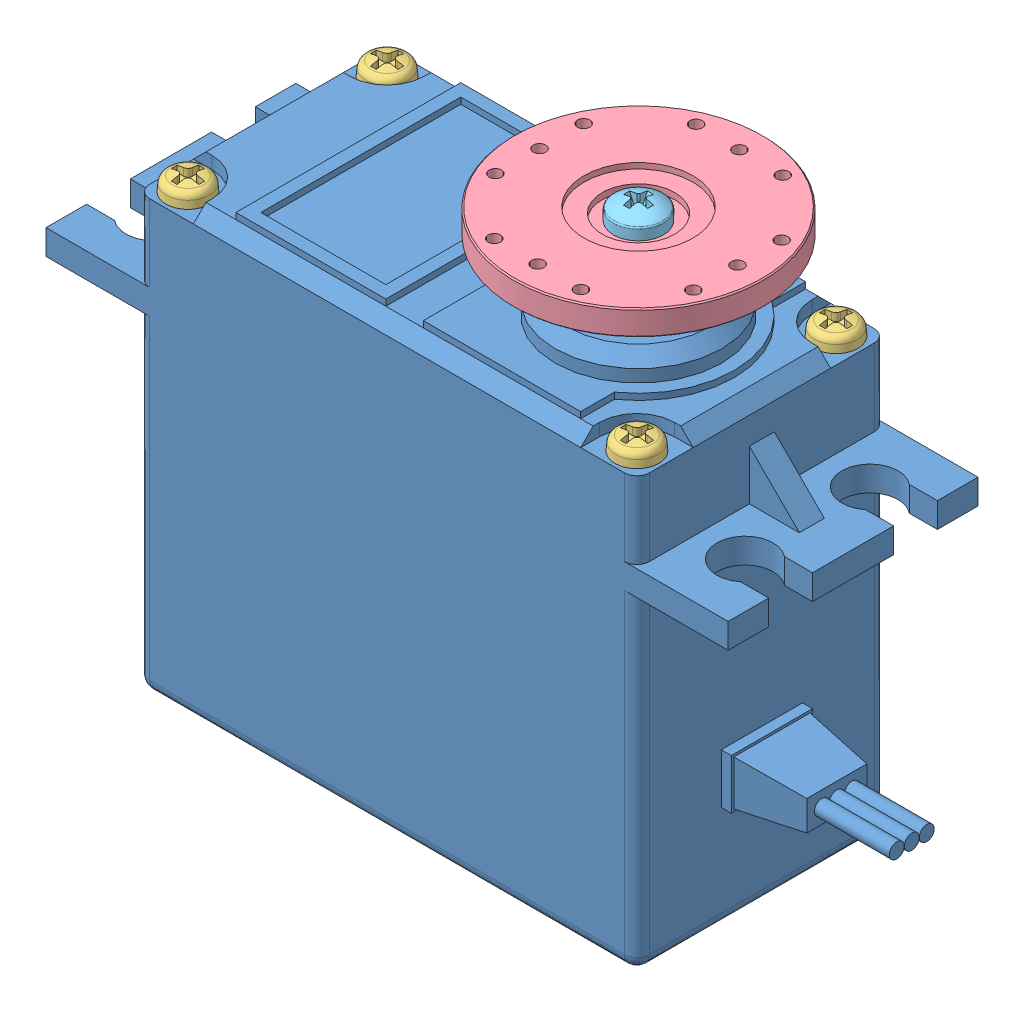
SolidWorks assembly servo_motor, configuration ﾃﾞﾌｫﾙﾄ. Lengths in mm.
Overall size (59.3 44.02 20.19).
8 component instances, 5 part files, 16 mates.
Components (placement in the parent):
- body-4: body [ﾃﾞﾌｫﾙﾄ] at (7.5879 13.1306 49.0124) size (59.3 37.9 20)
- spur gear_jis-4: spur gear_jis [JIS - Spur gear 0.25M 25T 20PA 6FW ---S25A75H50L2.0N] at (17.7129 55.0306 49.0124) x (0 -1 0) z (0 0 1) size (6 6.73 6.74)
- screw-6: screw [ﾃﾞﾌｫﾙﾄ] at (25.5576 47.5306 41.0427) x (0 -1 0) z (0 0 1) size (3.29 3.5 3.5)
- screw-7: screw [ﾃﾞﾌｫﾙﾄ] at (-10.3818 47.5306 41.0427) x (0 -1 0) z (0 0 1) size (3.29 3.5 3.5)
- screw-8: screw [ﾃﾞﾌｫﾙﾄ] at (25.5576 47.5306 56.9821) x (0 -1 0) z (0 0 1) size (3.29 3.5 3.5)
- screw-9: screw [ﾃﾞﾌｫﾙﾄ] at (-10.3818 47.5306 56.9821) x (0 -1 0) z (0 0 1) size (3.29 3.5 3.5)
- attachment-1: attachment [ﾃﾞﾌｫﾙﾄ] at (17.7129 56.5306 49.0124) x (-0.999954 0 -0.009565) z (-0.009565 0 0.999954) size (20 5 20)
- attachment_screw-1: attachment_screw [JIS B 1111 Cross recessed pan head screw - M2 x 5 - Z --5N] at (17.7129 57.1806 49.0124) x (0 -1 0) z (0 0 1) size (6.57 4 4)
Mates (geometry in assembly coordinates):
- 一致4: coincident anti-aligned: plane of ? through (-13.6217 41.271 50.2347) normal (0 1 0); plane of ? through (-13.6217 41.271 50.2347) normal (0 -1 0)
- 同心円4: concentric anti-aligned: circle of ?; circle of ?
- 一致6: coincident anti-aligned: plane of body-4 through (7.5879 47.5306 49.0124) normal (0 1 0); plane of screw-7 through (-8.6318 47.5306 41.0427) normal (0 -1 0)
- 同心円6: concentric aligned: cylinder of body-4 through (-10.3818 45.5306 41.0427) axis (0 1 0) radius 1; cylinder of screw-7 through (-10.3818 45.5306 41.0427) axis (0 1 0) radius 1
- 一致7: coincident anti-aligned: plane of body-4 through (7.5879 47.5306 49.0124) normal (0 1 0); plane of screw-6 through (27.3076 47.5306 41.0427) normal (0 -1 0)
- 同心円7: concentric aligned: cylinder of body-4 through (25.5576 45.5306 41.0427) axis (0 1 0) radius 1; cylinder of screw-6 through (25.5576 45.5306 41.0427) axis (0 1 0) radius 1
- 一致8: coincident anti-aligned: plane of body-4 through (7.5879 47.5306 49.0124) normal (0 1 0); plane of screw-8 through (27.3076 47.5306 56.9821) normal (0 -1 0)
- 同心円8: concentric aligned: cylinder of body-4 through (25.5576 45.5306 56.9821) axis (0 1 0) radius 1; cylinder of screw-8 through (25.5576 45.5306 56.9821) axis (0 1 0) radius 1
- 一致9: coincident anti-aligned: plane of body-4 through (7.5879 47.5306 49.0124) normal (0 1 0); plane of screw-9 through (-8.6318 47.5306 56.9821) normal (0 -1 0)
- 同心円9: concentric aligned: cylinder of body-4 through (-10.3818 45.5306 56.9821) axis (0 1 0) radius 1; cylinder of screw-9 through (-10.3818 45.5306 56.9821) axis (0 1 0) radius 1
- 一致10: coincident anti-aligned: plane of body-4 through (17.7129 49.0306 49.0124) normal (0 1 0); plane of spur gear_jis-4 through (17.7129 49.0306 49.0124) normal (0 -1 0)
- 同心円10: concentric anti-aligned: circle of body-4; circle of spur gear_jis-4
- 一致11: coincident anti-aligned: plane of spur gear_jis-4 through (17.7129 55.0306 49.0124) normal (0 1 0); plane of attachment-1 through (17.7129 55.0306 49.0124) normal (0 -1 0)
- 同心円11: concentric anti-aligned: cylinder of spur gear_jis-4 through (17.7129 65.0306 49.0124) axis (0 1 0) radius 3.375; cylinder of attachment-1 through (17.7129 55.0306 49.0124) axis (0 -1 0) radius 3.4004
- 一致12: coincident anti-aligned: plane of attachment-1 through (17.7129 55.5806 49.0124) normal (0 1 0); plane of attachment_screw-1 through (18.7129 55.5806 49.0124) normal (0 -1 0)
- 同心円12: concentric aligned: cylinder of spur gear_jis-4 through (17.7129 5.0305 49.0124) axis (0 1 0) radius 1; cylinder of attachment_screw-1 through (17.7129 82.5806 49.0124) axis (0 1 0) radius 1
